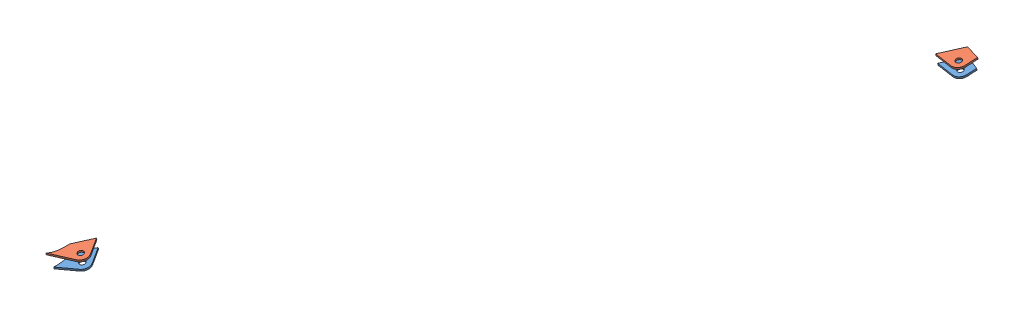
SolidWorks assembly PUTM-F-FR-MT-Aero-RW-Mountings, configuration Domyślna. Lengths in mm.
Overall size (440.97 126.76 591.66).
3 component instances, 3 part files, 0 mates.
Components (placement in the parent):
- PUTM-F-FR-MT-Aero-RW-Inside-Kinematics-1: PUTM-F-FR-MT-Aero-RW-Inside-Kinematics [Domyślna] at (0 365.9457 71.1326) x (1 0 0) z (0 0.981627 0.190809)
- PUTM-F-FR-MT-Aero-RW-Inside-Mounting-1: PUTM-F-FR-MT-Aero-RW-Inside-Mounting [Domyślna] at origin size (432.93 116.74 590.82)
- PUTM-F-FR-MT-Aero-RW-Outside-Mounting-1: PUTM-F-FR-MT-Aero-RW-Outside-Mounting [Domyślna] at origin size (440.97 116.74 590.82)
